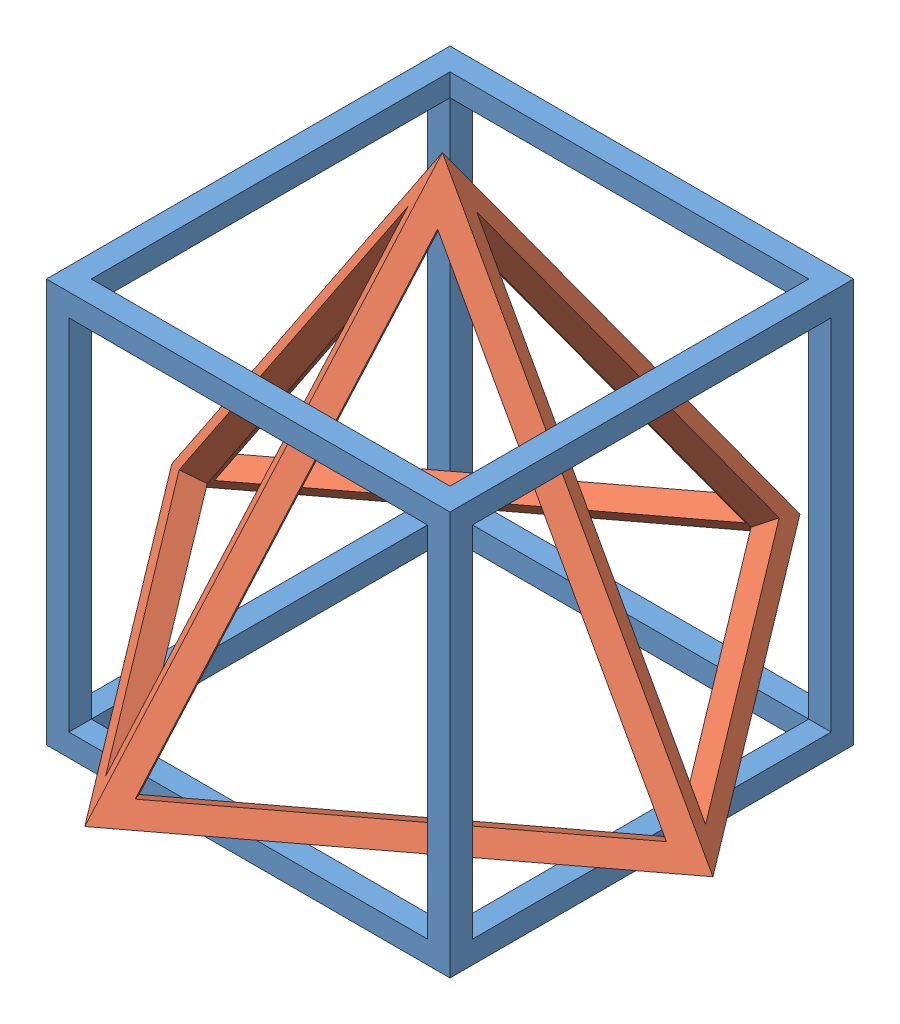
SolidWorks assembly ff, configuration Predeterminado. Lengths in mm.
Overall size (70.04 57.77 70.04).
2 component instances, 2 part files, 1 mates.
Components (placement in the parent):
- square-1: square [Predeterminado] at (-4.9634 -24.902 50) size (45 45 45)
- tria-1: tria [Predeterminado] at (-4.833 -17.1329 50.9822) x (-0.603346 0 -0.79748) z (0.79748 0 -0.603346) size (50 50 50)
Mates (geometry in assembly coordinates):
- Paralelo1: parallel anti-aligned: plane of square-1 through (-24.9634 -22.402 22.5) normal (0 1 0); plane of tria-1 through (-4.833 -17.1329 50.9822) normal (0 -1 0)
